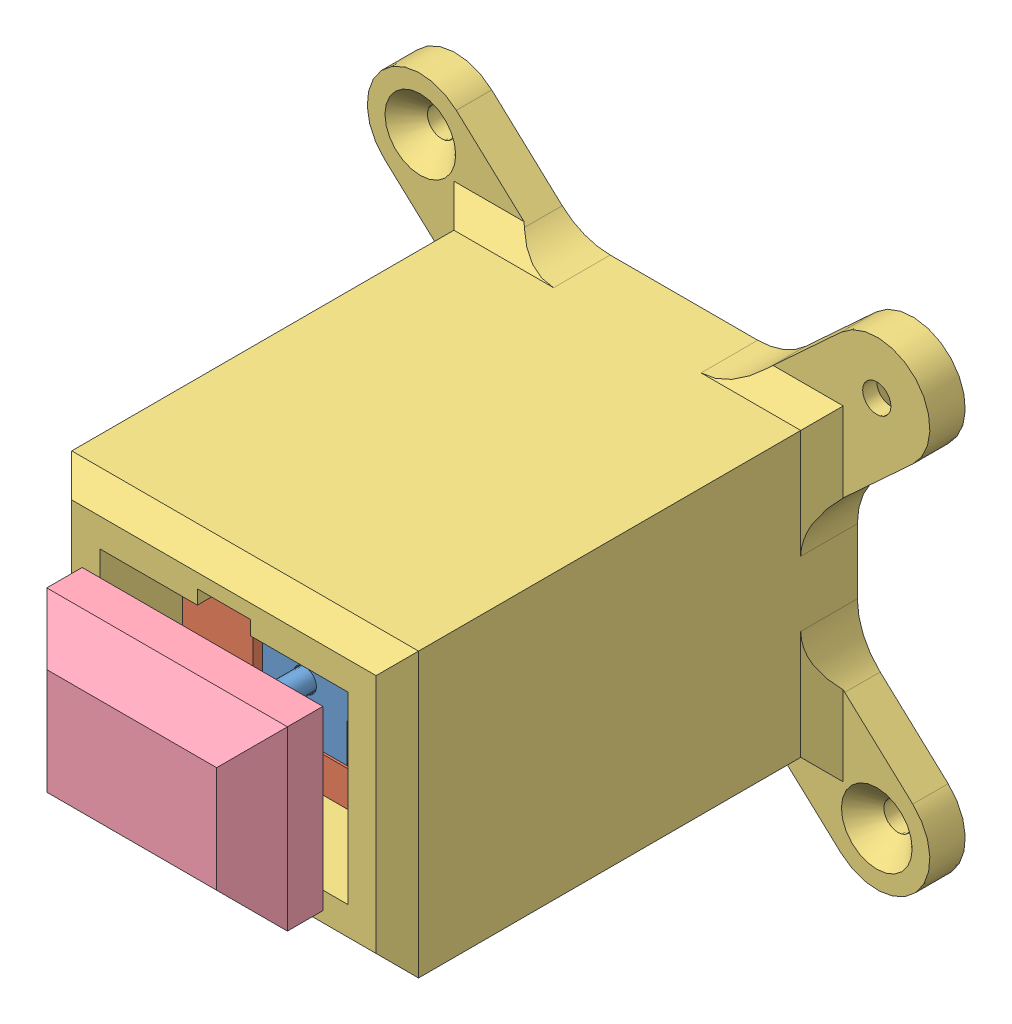
SolidWorks assembly Assem1, configuration Default. Lengths in mm.
Overall size (79.49 67.65 78.03).
5 component instances, 4 part files, 10 mates.
Components (placement in the parent):
- solenoid-1: solenoid [block] at (-50.0631 -17.286 23.5752) x (0 0 1) z (-1 0 0) size (30 15 15)
- solenoid-2: solenoid [stroke] at (-50.0631 -17.286 16.0279) x (0 0 1) z (-0.80019 -0.599747 0) size (57.04 6 6)
- p1-1: p1 [Default] at (-50.0631 -29.786 23.8752) x (-1 0 0) z (0 1 0) size (34 30 27)
- p2-1: p2 [Default] at (-50.0631 -17.286 5) size (79.49 67.65 65)
- p3-1: p3 [Default] at (-50.0631 -17.286 68.0279) size (34 25 10)
Mates (geometry in assembly coordinates):
- Concentric1: concentric aligned: cylinder of solenoid-1 through (-50.0631 -17.286 23.5752) axis (0 0 -1) radius 3; cylinder of solenoid-2 through (-50.0631 -17.286 16.0279) axis (0 0 -1) radius 3
- Concentric3: concentric aligned: cylinder of solenoid-1 through (-50.0631 -21.786 46.5752) axis (0 -1 0) radius 1.5; cylinder of p1-1 through (-50.0631 -24.786 46.5752) axis (0 -1 0) radius 1.75
- Concentric4: concentric aligned: cylinder of solenoid-1 through (-50.0631 -21.786 31.5752) axis (0 -1 0) radius 1.5; cylinder of p1-1 through (-50.0631 -24.786 31.5752) axis (0 -1 0) radius 1.75
- Coincident1: coincident anti-aligned: plane of solenoid-1 through (-56.0631 -24.786 23.5752) normal (0 -1 0); plane of p1-1 through (-50.0631 -24.786 31.5752) normal (0 1 0)
- Coincident3: coincident anti-aligned: line of solenoid-2 through (-50.0631 -17.286 68.0279) axis (0 0 -1); line of p2-1 through (-50.0631 -17.286 2.5) axis (0 0 1)
- Parallel1: parallel anti-aligned: plane of p1-1 through (-50.0631 -29.786 31.5752) normal (0 -1 0); plane of p2-1 through (-67.5631 -30.286 65) normal (0 1 0)
- Coincident5: coincident anti-aligned: plane of p2-1 through (-50.0631 -17.286 0) normal (0 0 -1)
- Concentric5: concentric aligned: cylinder of solenoid-2 through (-50.0631 -17.286 16.0279) axis (0 0 -1) radius 1.3; cylinder of p3-1 through (-50.0631 -17.286 78.0299) axis (0 0 -1) radius 1.5
- Coincident6: coincident anti-aligned: plane of solenoid-2 through (-48.8628 -16.3864 68.0279) normal (0 0 1); plane of p3-1 through (-50.0631 -17.286 68.0279) normal (0 0 -1)
- Parallel2: parallel anti-aligned: plane of p2-1 through (-67.5631 -30.286 65) normal (0 1 0); plane of p3-1 through (-67.0631 -29.786 78.0279) normal (0 -1 0)
